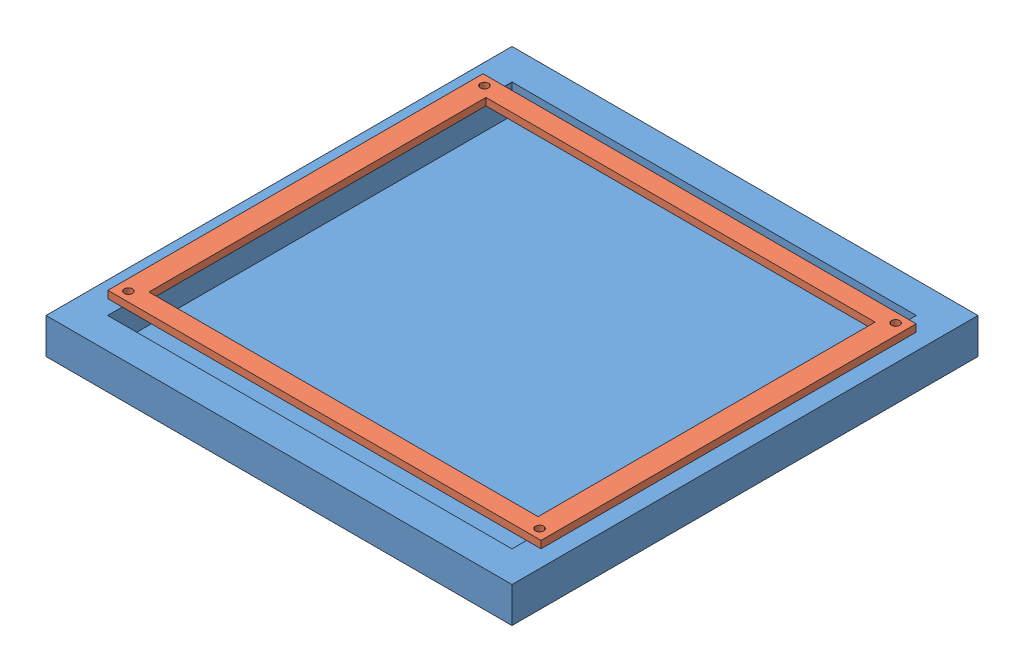
SolidWorks assembly TestFixtureAssembly, configuration Default. Lengths in mm.
Overall size (192 17.66 192).
2 component instances, 2 part files, 4 mates.
Components (placement in the parent):
- LED Matrix 64x64-1: LED Matrix 64x64 [Default] at (-16.7295 1.0909 3.1068) size (192 14.66 192)
- TestFrame-1: TestFrame [Default] at (-16.7295 15.7509 3.1068) x (1 0 0) z (0 1 0) size (178.47 154.56 3)
Mates (geometry in assembly coordinates):
- InPlace1: in place: plane of LED Matrix 64x64-1 through (-16.7295 15.7509 3.1068) normal (0 1 0); plane of ? through (0 15.7509 0) normal (0 1 0); moOrthogonalPlaneRef_w of LED Matrix 64x64-1 through (-16.7295 15.7509 3.1068) normal (0 1 0); plane of ? through (0 15.7509 0) normal (0 0 -1); plane of LED Matrix 64x64-1 through (-16.7295 15.7509 3.1068) normal (0 1 0); plane of ? through (0 15.7509 0) normal (1 0 0); plane of LED Matrix 64x64-1 through (-16.7295 15.7509 3.1068) normal (0 1 0); unknown of TestFrame-1
- Coincident1: coincident aligned: plane of ?; plane of ?
- Coincident2: coincident aligned: moOrthogonalPlaneRef_w of LED Matrix 64x64-1 through (-16.7295 15.7509 3.1068) normal (0 0 -1); plane of Part4^TestFixtureAssembly-1 through (-16.7295 15.7509 3.1068) normal (0 0 -1)
- Coincident3: coincident anti-aligned: moOrthogonalPlaneRef_w of LED Matrix 64x64-1 through (-16.7295 15.7509 3.1068) normal (-1 0 0); plane of Part4^TestFixtureAssembly-1 through (-16.7295 15.7509 3.1068) normal (1 0 0)
